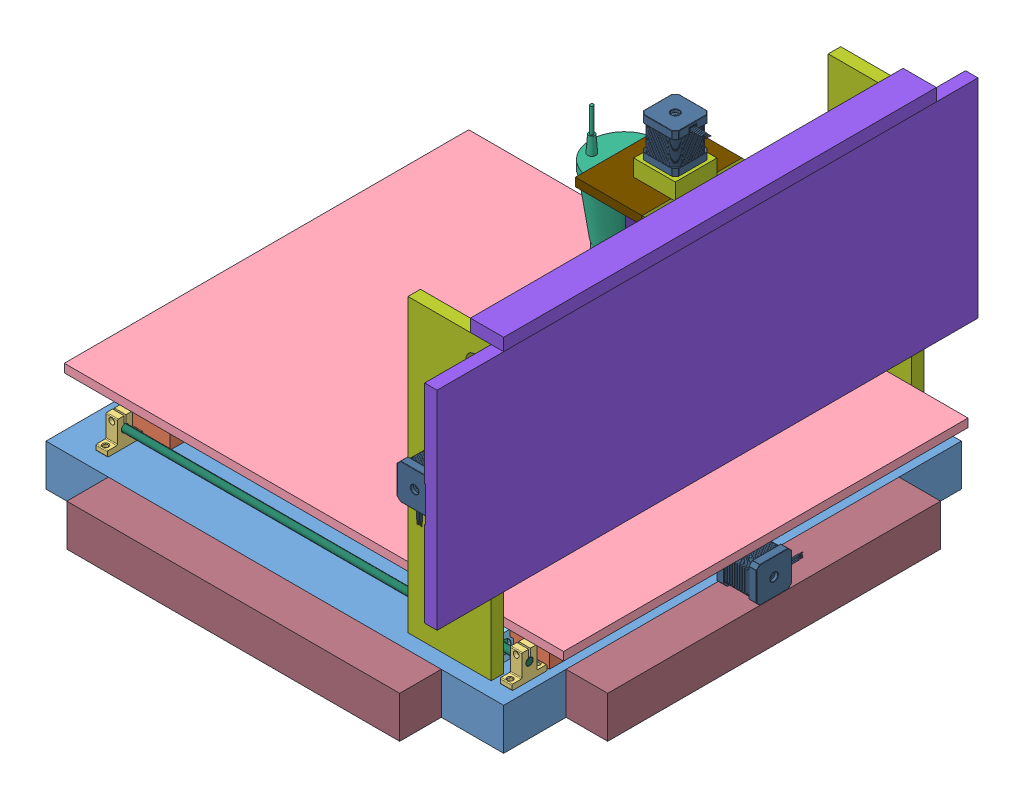
SolidWorks assembly CNCAssemV5, configuration Default. Lengths in mm.
Overall size (610 472.9 650).
95 component instances, 26 part files, 121 mates.
Components (placement in the parent):
- Lack borskiva 55x55-1: Lack borskiva 55x55 [Default] at origin size (550 50 550)
- Block-1: Block [Default] at (34 50 -65) size (50 50 50)
- Block-2: Block [Default] at (34 50 -435) size (50 50 50)
- Block-3: Block [Default] at (490 50 -65) size (50 50 50)
- Block-4: Block [Default] at (490 50 -435) size (50 50 50)
- Stånghållare-3: Stånghållare [Default] at (40 70 -509) x (0 0 -1) z (1 0 0) size (42 33.4 14)
- Stånghållare-4: Stånghållare [Default] at (526 70 -509) x (0 0 -1) z (1 0 0) size (42 33.4 14)
- Stånghållare-5: Stånghållare [Default] at (490 71.15 -275) x (0 0 -1) z (1 0 0) size (42 33.4 14)
- Stånghållare-6: Stånghållare [Default] at (24.9735 71.15 -275) x (0 0 -1) z (1 0 0) size (42 33.4 14)
- WorkPlate450mm-1: WorkPlate450mm [Default] at (-10 100 -32) size (600 10 486)
- Ball Bearing Assemby-1: Ball Bearing Assemby [Default] at (480 53 -520) x (0 1 0) z (1 0 0) size (34 21.75 30)
  - Ball Bearing Slider-1: Ball Bearing Slider [Default] at origin size (34 21.75 30)
  - Ball Bearing Imaginary Inlay-1: Ball Bearing Imaginary Inlay [Default] at (17 11 3.5) size (15 15 23)
- Ball Bearing Assemby-2: Ball Bearing Assemby [Default] at (420 53 -520) x (0 1 0) z (1 0 0) size (34 21.75 30)
  - Ball Bearing Slider-1: Ball Bearing Slider [Default] at origin size (34 21.75 30)
  - Ball Bearing Imaginary Inlay-1: Ball Bearing Imaginary Inlay [Default] at (17 11 3.5) size (15 15 23)
- Ball Bearing Assemby-3: Ball Bearing Assemby [Default] at (480 87 -30) x (0 -1 0) z (1 0 0) size (34 21.75 30)
  - Ball Bearing Slider-1: Ball Bearing Slider [Default] at origin size (34 21.75 30)
  - Ball Bearing Imaginary Inlay-1: Ball Bearing Imaginary Inlay [Default] at (17 11 3.5) size (15 15 23)
- Ball Bearing Assemby-4: Ball Bearing Assemby [Default] at (420 87 -30) x (0 -1 0) z (1 0 0) size (34 21.75 30)
  - Ball Bearing Slider-1: Ball Bearing Slider [Default] at origin size (34 21.75 30)
  - Ball Bearing Imaginary Inlay-1: Ball Bearing Imaginary Inlay [Default] at (17 11 3.5) size (15 15 23)
- YAxisSideBoard-2: YAxisSideBoard [Default] at (420 53 -520) size (100 350 15)
- YAxisSideBoard-3: YAxisSideBoard [Default] at (420 53 -15) size (100 350 15)
- YAxisRailMountBoard-3: YAxisRailMountBoard [Default] at (535 153 -585) x (0 1 0) z (1 0 0) size (250 650 15)
- YAxisBottomBoard-1: YAxisBottomBoard [Default] at (480 94 -520) x (-1 0 0) z (0 1 0) size (30 490 15)
- Stånghållare-8: Stånghållare [Default] at (500 373 -506) x (0 -1 0) z (0 0 -1) size (42 33.4 14)
- Stånghållare-9: Stånghållare [Default] at (500 183 -506) x (0 -1 0) z (0 0 -1) size (42 33.4 14)
- Stånghållare-10: Stånghållare [Default] at (500 373 -30) x (0 -1 0) z (0 0 -1) size (42 33.4 14)
- Stånghållare-11: Stånghållare [Default] at (500 183 -30) x (0 -1 0) z (0 0 -1) size (42 33.4 14)
- Stånghållare-12: Stånghållare [Default] at (500 278 -30) x (0 -1 0) z (0 0 -1) size (42 33.4 14)
- Stånghållare-13: Stånghållare [Default] at (500 278 -506) x (0 -1 0) z (0 0 -1) size (42 33.4 14)
- Nema 17  Stepper Motor length 48mm-1: Nema 17  Stepper Motor length 48mm [По умолчанию] at (600 71.15 -275) x (0 -1 0) z (0 0 -1) size (42.3 71.6 61.3)
- Nema 17  Stepper Motor length 48mm-2: Nema 17  Stepper Motor length 48mm [По умолчанию] at (500 278 57.1) x (-1 0 0) z (0 -1 0) size (42.3 71.6 61.3)
- Stånghållare-14: Stånghållare [Default] at (54 70 -41) x (0 0 1) z (-1 0 0) size (42 33.4 14)
- Ball Bearing Assemby-5: Ball Bearing Assemby [Default] at (489 390 -347.2552) x (0 -1 0) z (0 0 1) size (34 21.75 30)
  - Ball Bearing Slider-1: Ball Bearing Slider [Default] at origin size (34 21.75 30)
  - Ball Bearing Imaginary Inlay-1: Ball Bearing Imaginary Inlay [Default] at (17 11 3.5) size (15 15 23)
- Ball Bearing Assemby-6: Ball Bearing Assemby [Default] at (489 390 -277.2552) x (0 -1 0) z (0 0 1) size (34 21.75 30)
  - Ball Bearing Slider-1: Ball Bearing Slider [Default] at origin size (34 21.75 30)
  - Ball Bearing Imaginary Inlay-1: Ball Bearing Imaginary Inlay [Default] at (17 11 3.5) size (15 15 23)
- Ball Bearing Assemby-7: Ball Bearing Assemby [Default] at (489 200 -367.2552) x (0 -1 0) z (0 0 1) size (34 21.75 30)
  - Ball Bearing Slider-1: Ball Bearing Slider [Default] at origin size (34 21.75 30)
  - Ball Bearing Imaginary Inlay-1: Ball Bearing Imaginary Inlay [Default] at (17 11 3.5) size (15 15 23)
- Ball Bearing Assemby-8: Ball Bearing Assemby [Default] at (489 200 -277.2552) x (0 -1 0) z (0 0 1) size (34 21.75 30)
  - Ball Bearing Slider-1: Ball Bearing Slider [Default] at origin size (34 21.75 30)
  - Ball Bearing Imaginary Inlay-1: Ball Bearing Imaginary Inlay [Default] at (17 11 3.5) size (15 15 23)
- MotorToRodFastener 5x10mm-2: MotorToRodFastener 5x10mm [По умолчанию] at (527.65 71.15 -275) x (0 -0.254117 -0.967174) z (1 0 0) size (20 21.03 25.5)
- RodMountPlate1,15mm-1: RodMountPlate1,15mm [Default] at (38.9735 51.15 -249) x (0 0 1) z (1 0 0) size (55 1.15 20)
- RodMountPlate1,15mm-2: RodMountPlate1,15mm [Default] at (510 50 -304) x (0 0 -1) z (1 0 0) size (55 1.15 20)
- MotorToRodFastener 5x10mm-3: MotorToRodFastener 5x10mm [По умолчанию] at (500 278 -17.25) size (20 21.03 25.5)
- Lack Ben 5x55-1: Lack Ben 5x55 [Default] at (600 50 -75) x (0 -1 0) z (1 0 0) size (50 400 50)
- Lack Ben 5x55-2: Lack Ben 5x55 [Default] at (475 0 50) x (0 1 0) z (0 0 1) size (50 400 50)
- SkruvadStång500-3: SkruvadStång500 [По умолчанию] at (274.9 71.15 -275) size (500 8 8)
- Stång 500mm-8: Stång 500mm [Default] at (540 70 -509) x (-1 0 0) z (0 0 1) size (500 8 8)
- Stång 500mm-9: Stång 500mm [Default] at (540 70 -41) x (-1 0 0) z (0 0 1) size (500 8 8)
- Stång 500mm-10: Stång 500mm [Default] at (500 373 -520) x (0 0 1) z (0.999724 0.023498 0) size (500 8 8)
- Stång 500mm-11: Stång 500mm [Default] at (500 183 -520) x (0 0 1) z (0.999724 0.023498 0) size (500 8 8)
- SkruvadStång500-4: SkruvadStång500 [По умолчанию] at (500 278 -270) x (0 0 1) z (-0.769889 0.638178 0) size (500 8 8)
- MyDremmelTotalAssem-1: MyDremmelTotalAssem [Default] at (489 405.5 -237.2552) x (0 0 -1) z (0 1 0) size (120 141.99 327.4)
  - DremmelBoxBack-1: DremmelBoxBack [Default] at origin size (120 10 240)
  - DremmelBoxSide-1: DremmelBoxSide [Default] at (0 10 -230) x (0 1 0) z (1 0 0) size (20 220 10)
  - DremmelBoxSide-2: DremmelBoxSide [Default] at (110 10 -230) x (0 1 0) z (1 0 0) size (20 220 10)
  - DremmelBoxTop-2: DremmelBoxTop [Default] at (0 10 -10) x (1 0 0) z (0 -1 0) size (120 10 80)
  - Ball Bearing Assemby-1: Ball Bearing Assemby [Default] at (48 41 -172) x (-1 0 0) z (0 0 1) size (34 21.75 30)
    - Ball Bearing Slider-1: Ball Bearing Slider [Default] at origin size (34 21.75 30)
    - Ball Bearing Imaginary Inlay-1: Ball Bearing Imaginary Inlay [Default] at (17 11 3.5) size (15 15 23)
  - Ball Bearing Assemby-2: Ball Bearing Assemby [Default] at (48 41 -132) x (-1 0 0) z (0 0 1) size (34 21.75 30)
    - Ball Bearing Slider-1: Ball Bearing Slider [Default] at origin size (34 21.75 30)
    - Ball Bearing Imaginary Inlay-1: Ball Bearing Imaginary Inlay [Default] at (17 11 3.5) size (15 15 23)
  - Ball Bearing Assemby-3: Ball Bearing Assemby [Default] at (106 41 -172) x (-1 0 0) z (0 0 1) size (34 21.75 30)
    - Ball Bearing Slider-1: Ball Bearing Slider [Default] at origin size (34 21.75 30)
    - Ball Bearing Imaginary Inlay-1: Ball Bearing Imaginary Inlay [Default] at (17 11 3.5) size (15 15 23)
  - Ball Bearing Assemby-4: Ball Bearing Assemby [Default] at (106 41 -132) x (-1 0 0) z (0 0 1) size (34 21.75 30)
    - Ball Bearing Slider-1: Ball Bearing Slider [Default] at origin size (34 21.75 30)
    - Ball Bearing Imaginary Inlay-1: Ball Bearing Imaginary Inlay [Default] at (17 11 3.5) size (15 15 23)
  - SkruvadStång200-1: SkruvadStång200 [По умолчанию] at (60 30 -109.7) x (0 0 -1) z (0.908727 -0.417391 0) size (200 8 8)
  - Stång 200mm-1: Stång 200mm [Default] at (89 30 -10) x (0 0 -1) z (0.987596 0.157015 0) size (200 8 8)
  - Stånghållare-1: Stånghållare [Default] at (89 30 -24) size (42 33.4 14)
  - Stånghållare-2: Stånghållare [Default] at (89 30 -210) size (42 33.4 14)
  - Stånghållare-3: Stånghållare [Default] at (31 30 -10) x (-1 0 0) z (0 0 -1) size (42 33.4 14)
  - Stånghållare-4: Stånghållare [Default] at (31 30 -196) x (-1 0 0) z (0 0 -1) size (42 33.4 14)
  - Stång 200mm-2: Stång 200mm [Default] at (31 30 -210) x (0 0 1) z (0.080523 0.996753 0) size (200 8 8)
  - Stånghållare-6: Stånghållare [Default] at (60 30 -196) size (42 33.4 14)
  - Stånghållare-7: Stånghållare [Default] at (60 30 -38) size (42 33.4 14)
  - DremmelHolderMountPlate-1: DremmelHolderMountPlate [Default] at (10 41 -92) size (100 10 90)
  - DremmelBoxBottom-1: DremmelBoxBottom [Default] at (0 10 -240) x (1 0 0) z (0 -1 0) size (120 10 33)
  - DremmelHolder-1: DremmelHolder [Default] at (20 51 -192) x (1 0 0) z (0 -1 0) size (80 110 80)
  - Dremmel-1: Dremmel [Default] at (60 91 -92) x (0 1 0) z (-1 0 0) size (81.68 298 81.68)
  - ZAxisMotorSpacer-1: ZAxisMotorSpacer [Default] at (85 55 20) x (0 -1 0) z (1 0 0) size (50 20 50)
  - MotorToRodFastener 5x10mm-1: MotorToRodFastener 5x10mm [По умолчанию] at (60 30 -6.95) x (-0.177004 0.98421 0) z (0 0 1) size (20 21.03 25.5)
  - Nema 17  Stepper Motor length 48mm-2: Nema 17  Stepper Motor length 48mm [По умолчанию] at (60 30 67.4) x (-1 0 0) z (0 -1 0) size (42.3 71.6 61.3)
  - MotorToRodFastener 5x10mm-3: MotorToRodFastener 5x10mm [По умолчанию] at (60 30 -212.45) x (0.815261 0.579094 0) z (0 0 -1) size (20 21.03 25.5)
- Stånghållare-15: Stånghållare [Default] at (540 70 -41) x (0 0 1) z (-1 0 0) size (42 33.4 14)
- TopCoardFeederBoard-2: TopCoardFeederBoard [Default] at (495 403 -15) size (40 15 520)
Mates (geometry in assembly coordinates):
- Coincident7: coincident: plane of Lack borskiva 55x55-1 through (0 50 0) normal (0 1 0); plane of Stånghållare-4 through (540 50 -488) normal (0 -1 0)
- Coincident9: coincident: plane of Lack borskiva 55x55-1 through (0 50 0) normal (0 1 0); plane of Stånghållare-3 through (54 50 -488) normal (0 -1 0)
- Coincident15: coincident: plane of Lack borskiva 55x55-1 through (0 50 0) normal (0 1 0); plane of Block-2 through (34 50 -435) normal (0 -1 0)
- Coincident16: coincident: plane of Lack borskiva 55x55-1 through (0 50 0) normal (0 1 0); plane of Block-4 through (490 50 -435) normal (0 -1 0)
- Coincident17: coincident: plane of Lack borskiva 55x55-1 through (0 50 0) normal (0 1 0); plane of Block-3 through (490 50 -65) normal (0 -1 0)
- Coincident18: coincident: plane of Lack borskiva 55x55-1 through (0 50 0) normal (0 1 0); plane of Block-1 through (34 50 -65) normal (0 -1 0)
- Distance1: distance = 65 mm: line of Block-2 through (84 50 -485) axis (-1 0 0); line of Lack borskiva 55x55-1 through (550 50 -550) axis (-1 0 0)
- Distance2: distance = 34 mm: line of Block-2 through (34 50 -485) axis (0 0 1); line of Lack borskiva 55x55-1 through (0 50 -550) axis (0 0 1)
- Distance3: distance = 65 mm: line of Block-4 through (540 50 -485) axis (-1 0 0); line of Lack borskiva 55x55-1 through (550 50 -550) axis (-1 0 0)
- Distance4: distance = 10 mm: line of Block-4 through (540 50 -435) axis (0 0 -1); line of Lack borskiva 55x55-1 through (550 50 0) axis (0 0 -1)
- Distance5: distance = 10 mm: line of Block-3 through (540 50 -65) axis (0 0 -1); line of Lack borskiva 55x55-1 through (550 50 0) axis (0 0 -1)
- Distance6: distance = 65 mm: line of Block-3 through (490 50 -65) axis (1 0 0); line of Lack borskiva 55x55-1 through (550 0 50) axis (0 1 0)
- Distance7: distance = 65 mm: line of Block-1 through (34 50 -65) axis (1 0 0); line of Lack borskiva 55x55-1 through (550 0 50) axis (0 1 0)
- Distance8: distance = 34 mm: line of Block-1 through (34 50 -115) axis (0 0 1); line of Lack borskiva 55x55-1 through (0 50 -550) axis (0 0 1)
- Coincident27: coincident: plane of Block-4 through (490 100 -435) normal (0 1 0); plane of WorkPlate450mm-1 through (-10 100 -32) normal (0 -1 0)
- Coincident42: coincident: plane of Ball Bearing Assemby-1/Ball Bearing Slider-1 through (510 61 -520) normal (0 0 -1); plane of YAxisSideBoard-2 through (420 403 -520) normal (0 0 1)
- Coincident43: coincident: plane of Ball Bearing Assemby-2/Ball Bearing Slider-1 through (450 79 -520) normal (0 0 -1); plane of YAxisSideBoard-2 through (420 403 -520) normal (0 0 1)
- Coincident44: coincident: line of Ball Bearing Assemby-2/Ball Bearing Slider-1 through (450 53 -520) axis (-1 0 0); line of YAxisSideBoard-2 through (420 53 -520) axis (1 0 0)
- Coincident47: coincident: plane of Ball Bearing Assemby-4/Ball Bearing Slider-1 through (450 61 -30) normal (0 0 1); plane of YAxisSideBoard-3 through (420 403 -30) normal (0 0 -1)
- Coincident48: coincident: plane of Ball Bearing Assemby-3/Ball Bearing Slider-1 through (510 79 -30) normal (0 0 1); plane of YAxisSideBoard-3 through (420 403 -30) normal (0 0 -1)
- Coincident49: coincident: line of Ball Bearing Assemby-4/Ball Bearing Slider-1 through (450 53 -30) axis (-1 0 0); line of YAxisSideBoard-3 through (520 53 -30) axis (-1 0 0)
- Coincident63: coincident: plane of YAxisSideBoard-3 through (520 403 -15) normal (1 0 0); plane of YAxisRailMountBoard-3 through (520 153 65) normal (-1 0 0)
- Coincident64: coincident: plane of YAxisSideBoard-2 through (520 403 -520) normal (1 0 0); plane of YAxisRailMountBoard-3 through (520 153 65) normal (-1 0 0)
- Distance24: distance = 50 mm: plane of YAxisSideBoard-2 through (420 403 -535) normal (0 0 -1); plane of YAxisRailMountBoard-3 through (535 153 -585) normal (0 0 -1)
- Coincident70: coincident: plane of YAxisSideBoard-3 through (420 403 -30) normal (0 0 -1); plane of YAxisBottomBoard-1 through (480 94 -30) normal (0 0 1)
- Coincident78: coincident: plane of YAxisRailMountBoard-3 through (520 153 65) normal (-1 0 0); plane of Stånghållare-8 through (520 394 -520) normal (1 0 0)
- Coincident79: coincident: plane of YAxisSideBoard-2 through (420 403 -520) normal (0 0 1); plane of Stånghållare-8 through (500 373 -520) normal (0 0 -1)
- Coincident80: coincident: plane of YAxisSideBoard-2 through (420 403 -520) normal (0 0 1); plane of Stånghållare-9 through (500 183 -520) normal (0 0 -1)
- Coincident81: coincident: plane of YAxisRailMountBoard-3 through (520 153 65) normal (-1 0 0); plane of Stånghållare-9 through (520 204 -520) normal (1 0 0)
- Coincident82: coincident: plane of YAxisRailMountBoard-3 through (520 153 65) normal (-1 0 0); plane of Stånghållare-13 through (520 299 -520) normal (1 0 0)
- Coincident83: coincident: plane of YAxisSideBoard-2 through (420 403 -520) normal (0 0 1); plane of Stånghållare-13 through (500 278 -520) normal (0 0 -1)
- Coincident84: coincident: plane of YAxisRailMountBoard-3 through (520 153 65) normal (-1 0 0); plane of Stånghållare-10 through (520 394 -44) normal (1 0 0)
- Coincident85: coincident: plane of YAxisRailMountBoard-3 through (520 153 65) normal (-1 0 0); plane of Stånghållare-12 through (520 299 -44) normal (1 0 0)
- Coincident86: coincident: plane of YAxisRailMountBoard-3 through (520 153 65) normal (-1 0 0); plane of Stånghållare-11 through (520 204 -44) normal (1 0 0)
- Coincident87: coincident: plane of YAxisSideBoard-3 through (420 403 -30) normal (0 0 -1); plane of Stånghållare-10 through (500 373 -30) normal (0 0 1)
- Coincident88: coincident: plane of YAxisSideBoard-3 through (420 403 -30) normal (0 0 -1); plane of Stånghållare-12 through (500 278 -30) normal (0 0 1)
- Coincident89: coincident: plane of YAxisSideBoard-3 through (420 403 -30) normal (0 0 -1); plane of Stånghållare-11 through (500 183 -30) normal (0 0 1)
- Coincident108: coincident: plane of Lack borskiva 55x55-1 through (0 50 0) normal (0 1 0); plane of Stånghållare-14 through (40 50 -62) normal (0 -1 0)
- LimitDistance2: limit distance = 366 mm: plane of YAxisBottomBoard-1 through (450 94 -30) normal (-1 0 0); plane of Block-1 through (84 100 -65) normal (1 0 0)
- Parallel13: parallel: plane of YAxisRailMountBoard-3 through (520 153 65) normal (-1 0 0); plane of Nema 17  Stepper Motor length 48mm-2 through (521.15 278 47.9) normal (1 0 0)
- Concentric40: concentric: cylinder of Nema 17  Stepper Motor length 48mm-1 through (528.4 71.15 -275) axis (1 0 0) radius 2.5; cylinder of MotorToRodFastener 5x10mm-2 through (540.4 71.15 -275) axis (-1 0 0) radius 2.5
- Coincident133: coincident: plane of Lack borskiva 55x55-1 through (0 50 0) normal (0 1 0); plane of RodMountPlate1,15mm-1 through (38.9735 50 -249) normal (0 -1 0)
- Coincident134: coincident: plane of Stånghållare-6 through (38.9735 51.15 -254) normal (0 -1 0); plane of RodMountPlate1,15mm-1 through (38.9735 51.15 -249) normal (0 1 0)
- Coincident135: coincident: line of Stånghållare-6 through (38.9735 51.15 -255) axis (0 0 -1); line of RodMountPlate1,15mm-1 through (38.9735 51.15 -304) axis (0 0 1)
- Distance63: distance = 5 mm: plane of Stånghållare-6 through (38.9735 57.85 -254) normal (0 0 1); plane of RodMountPlate1,15mm-1 through (38.9735 50 -249) normal (0 0 1)
- Coincident137: coincident: plane of Lack borskiva 55x55-1 through (0 50 0) normal (0 1 0); plane of RodMountPlate1,15mm-2 through (510 50 -304) normal (0 -1 0)
- Coincident139: coincident: plane of Stånghållare-5 through (504 51.15 -254) normal (0 -1 0); plane of RodMountPlate1,15mm-2 through (510 51.15 -304) normal (0 1 0)
- Coincident140: coincident: line of Stånghållare-5 through (490 51.15 -255) axis (0 0 -1); line of RodMountPlate1,15mm-2 through (490 51.15 -304) axis (0 0 1)
- Distance64: distance = 5 mm: plane of Stånghållare-5 through (504 57.85 -254) normal (0 0 1); plane of RodMountPlate1,15mm-2 through (510 51.15 -249) normal (0 0 1)
- Distance65: distance = 12 mm: plane of Nema 17  Stepper Motor length 48mm-1 through (528.4 71.15 -275) normal (-1 0 0); plane of MotorToRodFastener 5x10mm-2 through (540.4 71.15 -275) normal (1 0 0)
- Coincident149: coincident: plane of YAxisSideBoard-2 through (420 403 -520) normal (0 0 1); plane of YAxisBottomBoard-1 through (480 94 -520) normal (0 0 -1)
- Concentric43: concentric: circle of YAxisSideBoard-2; circle of Stånghållare-8
- Concentric44: concentric: circle of YAxisSideBoard-2; circle of Stånghållare-13
- Concentric45: concentric: circle of YAxisSideBoard-2; circle of Stånghållare-9
- Distance72: distance = 50 mm: plane of WorkPlate450mm-1 through (590 110 -32) normal (1 0 0); plane of Block-3 through (540 100 -65) normal (1 0 0)
- Distance73: distance = 33 mm: plane of WorkPlate450mm-1 through (-10 110 -32) normal (0 0 1); plane of Block-3 through (490 100 -65) normal (0 0 1)
- Coincident159: coincident: plane of Lack borskiva 55x55-1 through (550 50 0) normal (1 0 0); plane of Lack Ben 5x55-1 through (550 50 -475) normal (-1 0 0)
- Coincident160: coincident: line of Lack borskiva 55x55-1 through (550 50 0) axis (0 0 -1); line of Lack Ben 5x55-1 through (550 50 -475) axis (0 0 1)
- Distance74: distance = 75 mm: plane of Lack Ben 5x55-1 through (600 50 -475) normal (0 0 -1); plane of Lack borskiva 55x55-1 through (0 50 -550) normal (0 0 -1)
- Coincident162: coincident: plane of Nema 17  Stepper Motor length 48mm-1 through (590.8 50 -275) normal (0 -1 0); plane of Lack Ben 5x55-1 through (600 50 -475) normal (0 1 0)
- Coincident165: coincident: plane of Nema 17  Stepper Motor length 48mm-1 through (600 71.15 -275) normal (1 0 0); plane of Lack Ben 5x55-1 through (600 50 -475) normal (1 0 0)
- Distance75: distance = 178.85 mm: plane of Nema 17  Stepper Motor length 48mm-1 through (590.8 71.15 -296.15) normal (0 0 -1); plane of Lack Ben 5x55-1 through (600 50 -475) normal (0 0 -1)
- Coincident168: coincident: plane of YAxisRailMountBoard-3 through (521.15 153 -585) normal (-1 0 0); plane of Nema 17  Stepper Motor length 48mm-2 through (521.15 278 47.9) normal (1 0 0)
- Coincident169: coincident: plane of Block-3 through (490 100 -65) normal (-1 0 0); plane of Stånghållare-5 through (490 71.15 -275) normal (-1 0 0)
- Distance78: distance = 10 mm: plane of Stånghållare-4 through (540 70 -509) normal (1 0 0); plane of Lack borskiva 55x55-1 through (550 50 0) normal (1 0 0)
- Coincident179: coincident: plane of Lack borskiva 55x55-1 through (0 50 0) normal (0 0 1); plane of Lack Ben 5x55-2 through (75 0 0) normal (0 0 -1)
- Coincident180: coincident: plane of Lack borskiva 55x55-1 through (0 50 0) normal (0 1 0); plane of Lack Ben 5x55-2 through (75 50 50) normal (0 1 0)
- Distance79: distance = 75 mm: plane of Lack Ben 5x55-2 through (75 0 50) normal (-1 0 0); plane of Lack borskiva 55x55-1 through (0 50 0) normal (-1 0 0)
- Concentric52: concentric: cylinder of Stånghållare-6 through (38.9735 71.15 -275) axis (-1 0 0) radius 4; cylinder of SkruvadStång500-3 through (24.9 71.15 -275) axis (-1 0 0) radius 4
- Concentric53: concentric: cylinder of Ball Bearing Assemby-4/Ball Bearing Imaginary Inlay-1 through (423.5 70 -41) axis (1 0 0) radius 4.05; cylinder of Stång 500mm-9 through (40 70 -41) axis (1 0 0) radius 4
- Concentric54: concentric: cylinder of Ball Bearing Assemby-2/Ball Bearing Imaginary Inlay-1 through (423.5 70 -509) axis (1 0 0) radius 4.05; cylinder of Stång 500mm-8 through (40 70 -509) axis (1 0 0) radius 4
- Concentric55: concentric: cylinder of Stånghållare-4 through (540 70 -509) axis (-1 0 0) radius 4; cylinder of Stång 500mm-8 through (40 70 -509) axis (1 0 0) radius 4
- Coincident182: coincident: plane of Stånghållare-4 through (540 70 -509) normal (1 0 0); plane of Stång 500mm-8 through (540 70 -509) normal (1 0 0)
- Concentric56: concentric: cylinder of Stånghållare-3 through (54 70 -509) axis (-1 0 0) radius 4; cylinder of Stång 500mm-8 through (40 70 -509) axis (1 0 0) radius 4
- Coincident184: coincident: plane of Stånghållare-3 through (40 70 -509) normal (-1 0 0); plane of Stång 500mm-8 through (40 70 -509) normal (-1 0 0)
- Distance80: distance = 10 mm: plane of SkruvadStång500-3 through (524.9 75.15 -275) normal (1 0 0); plane of MotorToRodFastener 5x10mm-2 through (514.9 71.15 -275) normal (-1 0 0)
- Coincident186: coincident: plane of Stånghållare-14 through (40 70 -41) normal (-1 0 0); plane of Stång 500mm-9 through (40 70 -41) normal (-1 0 0)
- Concentric57: concentric: cylinder of Ball Bearing Assemby-3/Ball Bearing Imaginary Inlay-1 through (483.5 70 -41) axis (1 0 0) radius 4.05; cylinder of Stång 500mm-9 through (40 70 -41) axis (1 0 0) radius 4
- Concentric59: concentric: cylinder of Ball Bearing Assemby-1/Ball Bearing Imaginary Inlay-1 through (483.5 70 -509) axis (1 0 0) radius 4.05; cylinder of Stång 500mm-8 through (40 70 -509) axis (1 0 0) radius 4
- Concentric60: concentric: cylinder of Stånghållare-10 through (500 373 -44) axis (0 0 1) radius 4; cylinder of Stång 500mm-10 through (500 373 -20) axis (0 0 -1) radius 4
- Coincident188: coincident: plane of YAxisSideBoard-2 through (420 403 -520) normal (0 0 1); plane of Stång 500mm-10 through (500 373 -520) normal (0 0 -1)
- Concentric61: concentric: cylinder of Stånghållare-8 through (500 373 -520) axis (0 0 1) radius 4; cylinder of Stång 500mm-10 through (500 373 -20) axis (0 0 -1) radius 4
- Concentric62: concentric: cylinder of Stånghållare-9 through (500 183 -520) axis (0 0 1) radius 4; cylinder of Stång 500mm-11 through (500 183 -20) axis (0 0 -1) radius 4
- Concentric63: concentric: cylinder of Stånghållare-11 through (500 183 -44) axis (0 0 1) radius 4; cylinder of Stång 500mm-11 through (500 183 -20) axis (0 0 -1) radius 4
- Concentric64: concentric: cylinder of Ball Bearing Assemby-5/Ball Bearing Slider-1 through (500 373 -317.2552) axis (0 0 1) radius 7.5; cylinder of Stång 500mm-10 through (500 373 -20) axis (0 0 -1) radius 4
- Concentric65: concentric: cylinder of Ball Bearing Assemby-6/Ball Bearing Imaginary Inlay-1 through (500 373 -273.7552) axis (0 0 1) radius 4.05; cylinder of Stång 500mm-10 through (500 373 -20) axis (0 0 -1) radius 4
- Concentric66: concentric: cylinder of Ball Bearing Assemby-7/Ball Bearing Imaginary Inlay-1 through (500 183 -363.7552) axis (0 0 1) radius 4.05; cylinder of Stång 500mm-11 through (500 183 -20) axis (0 0 -1) radius 4
- Concentric67: concentric: cylinder of Ball Bearing Assemby-8/Ball Bearing Imaginary Inlay-1 through (500 183 -273.7552) axis (0 0 1) radius 4.05; cylinder of Stång 500mm-11 through (500 183 -20) axis (0 0 -1) radius 4
- Coincident190: coincident: plane of YAxisSideBoard-2 through (420 403 -520) normal (0 1 0); plane of YAxisRailMountBoard-3 through (535 403 65) normal (0 1 0)
- Concentric68: concentric: cylinder of Stånghållare-13 through (500 278 -520) axis (0 0 1) radius 4; cylinder of SkruvadStång500-4 through (500 278 -520) axis (0 0 -1) radius 4
- Concentric69: concentric: cylinder of Stånghållare-12 through (500 278 -44) axis (0 0 1) radius 4; cylinder of SkruvadStång500-4 through (500 278 -520) axis (0 0 -1) radius 4
- Distance81: distance = 10 mm: plane of SkruvadStång500-4 through (502.5527 281.0796 -20) normal (0 0 1); plane of MotorToRodFastener 5x10mm-3 through (500 278 -30) normal (0 0 -1)
- Distance82: distance = 7 mm: plane of YAxisBottomBoard-1 through (480 94 -30) normal (0 1 0); plane of Ball Bearing Assemby-4/Ball Bearing Slider-1 through (450 87 -30) normal (0 1 0)
- Concentric73: concentric: cylinder of MotorToRodFastener 5x10mm-3 through (500 278 -11.6132) axis (0 0 1) radius 5; cylinder of SkruvadStång500-4 through (500 278 -520) axis (0 0 -1) radius 4
- Coincident194: coincident: plane of Ball Bearing Assemby-5/Ball Bearing Slider-1 through (489 364 -317.2552) normal (-1 0 0); plane of MyDremmelTotalAssem-1/DremmelBoxBack-1 through (489 405.5 -237.2552) normal (1 0 0)
- Coincident195: coincident: plane of Ball Bearing Assemby-6/Ball Bearing Slider-1 through (489 382 -247.2552) normal (-1 0 0); plane of MyDremmelTotalAssem-1/DremmelBoxBack-1 through (489 405.5 -237.2552) normal (1 0 0)
- Coincident196: coincident: plane of Ball Bearing Assemby-8/Ball Bearing Slider-1 through (489 174 -247.2552) normal (-1 0 0); plane of MyDremmelTotalAssem-1/DremmelBoxBack-1 through (489 405.5 -237.2552) normal (1 0 0)
- Coincident197: coincident: plane of Ball Bearing Assemby-7/Ball Bearing Slider-1 through (489 192 -337.2552) normal (-1 0 0); plane of MyDremmelTotalAssem-1/DremmelBoxBack-1 through (489 405.5 -237.2552) normal (1 0 0)
- Distance83: distance = 10 mm: plane of Ball Bearing Assemby-7/Ball Bearing Slider-1 through (489 200 -367.2552) normal (0 0 -1); plane of MyDremmelTotalAssem-1/DremmelBoxBack-1 through (479 405.5 -357.2552) normal (0 0 -1)
- Distance84: distance = 10 mm: plane of Ball Bearing Assemby-8/Ball Bearing Slider-1 through (489 200 -247.2552) normal (0 0 1); plane of MyDremmelTotalAssem-1/DremmelBoxBack-1 through (479 405.5 -237.2552) normal (0 0 1)
- Distance85: distance = 10 mm: plane of Ball Bearing Assemby-5/Ball Bearing Slider-1 through (489 390 -347.2552) normal (0 0 -1); plane of MyDremmelTotalAssem-1/DremmelBoxBack-1 through (479 405.5 -357.2552) normal (0 0 -1)
- Distance86: distance = 10 mm: plane of Ball Bearing Assemby-6/Ball Bearing Slider-1 through (489 390 -247.2552) normal (0 0 1); plane of MyDremmelTotalAssem-1/DremmelBoxBack-1 through (479 405.5 -237.2552) normal (0 0 1)
- Distance88: distance = 2 mm: plane of MyDremmelTotalAssem-1/DremmelBoxBack-1 through (479 165.5 -237.2552) normal (0 -1 0); plane of Ball Bearing Assemby-8/Ball Bearing Slider-1 through (496.75 167.5 -247.2552) normal (0 -1 0)
- Concentric76: concentric: cylinder of Stång 500mm-9 through (40 70 -41) axis (1 0 0) radius 4; cylinder of Stånghållare-15 through (526 70 -41) axis (1 0 0) radius 4
- Coincident205: coincident: plane of Stång 500mm-9 through (540 70 -41) normal (1 0 0); plane of Stånghållare-15 through (540 70 -41) normal (1 0 0)
- Concentric77: concentric: cylinder of Stånghållare-14 through (40 70 -41) axis (1 0 0) radius 4; cylinder of Stång 500mm-9 through (40 70 -41) axis (1 0 0) radius 4
- Distance89: distance = 7 mm: plane of Ball Bearing Assemby-1/Ball Bearing Slider-1 through (510 87 -520) normal (0 1 0); plane of YAxisBottomBoard-1 through (480 94 -30) normal (0 1 0)
- Coincident207: coincident: plane of Stånghållare-9 through (500 183 -520) normal (0 0 -1); plane of Stång 500mm-11 through (500 183 -520) normal (0 0 -1)
- Coincident208: coincident: plane of Stånghållare-13 through (500 278 -520) normal (0 0 -1); plane of SkruvadStång500-4 through (500 278 -520) normal (0 0 -1)
- Distance90: distance = 20 mm: plane of Stånghållare-3 through (54 50 -530) normal (0 0 -1); plane of Lack borskiva 55x55-1 through (0 50 -550) normal (0 0 -1)
- Distance91: distance = 10 mm: plane of Nema 17  Stepper Motor length 48mm-2 through (500 278 -14.5) normal (0 0 -1); plane of MotorToRodFastener 5x10mm-3 through (500 278 -4.5) normal (0 0 1)
- Concentric80: concentric: cylinder of Nema 17  Stepper Motor length 48mm-2 through (500 278 -14.5) axis (0 0 1) radius 2.5; cylinder of MotorToRodFastener 5x10mm-3 through (500 278 -4.5) axis (0 0 -1) radius 2.5
- LimitDistance3: limit distance = 148.7448 mm: plane of MyDremmelTotalAssem-1/DremmelBoxBack-1 through (479 405.5 -357.2552) normal (0 0 -1); plane of Stånghållare-8 through (500 373 -506) normal (0 0 1)
- Coincident215: coincident: plane of Ball Bearing Assemby-2/Ball Bearing Slider-1 through (420 53 -520) normal (-1 0 0); plane of YAxisSideBoard-2 through (420 403 -520) normal (-1 0 0)
- Distance94: distance = 10 mm: plane of Ball Bearing Assemby-3/Ball Bearing Slider-1 through (510 87 -30) normal (1 0 0); plane of YAxisSideBoard-3 through (520 403 -15) normal (1 0 0)
- Coincident214: coincident: plane of Ball Bearing Assemby-4/Ball Bearing Slider-1 through (420 87 -30) normal (-1 0 0); plane of YAxisSideBoard-3 through (420 403 -15) normal (-1 0 0)
- Coincident213: coincident: plane of Ball Bearing Assemby-4/Ball Bearing Slider-1 through (450 87 -30) normal (1 0 0); plane of YAxisBottomBoard-1 through (450 94 -30) normal (-1 0 0)
- Distance96: distance = 10 mm: plane of Ball Bearing Assemby-1/Ball Bearing Slider-1 through (510 53 -520) normal (1 0 0); plane of YAxisSideBoard-2 through (520 403 -520) normal (1 0 0)
- Coincident216: coincident: plane of YAxisRailMountBoard-3 through (535 403 65) normal (0 1 0); plane of TopCoardFeederBoard-2 through (495 403 -15) normal (0 -1 0)
- Coincident217: coincident: plane of YAxisRailMountBoard-3 through (535 153 65) normal (1 0 0); plane of TopCoardFeederBoard-2 through (535 418 -15) normal (1 0 0)
- Coincident218: coincident: plane of YAxisSideBoard-2 through (420 403 -535) normal (0 0 -1); plane of TopCoardFeederBoard-2 through (495 418 -535) normal (0 0 -1)
